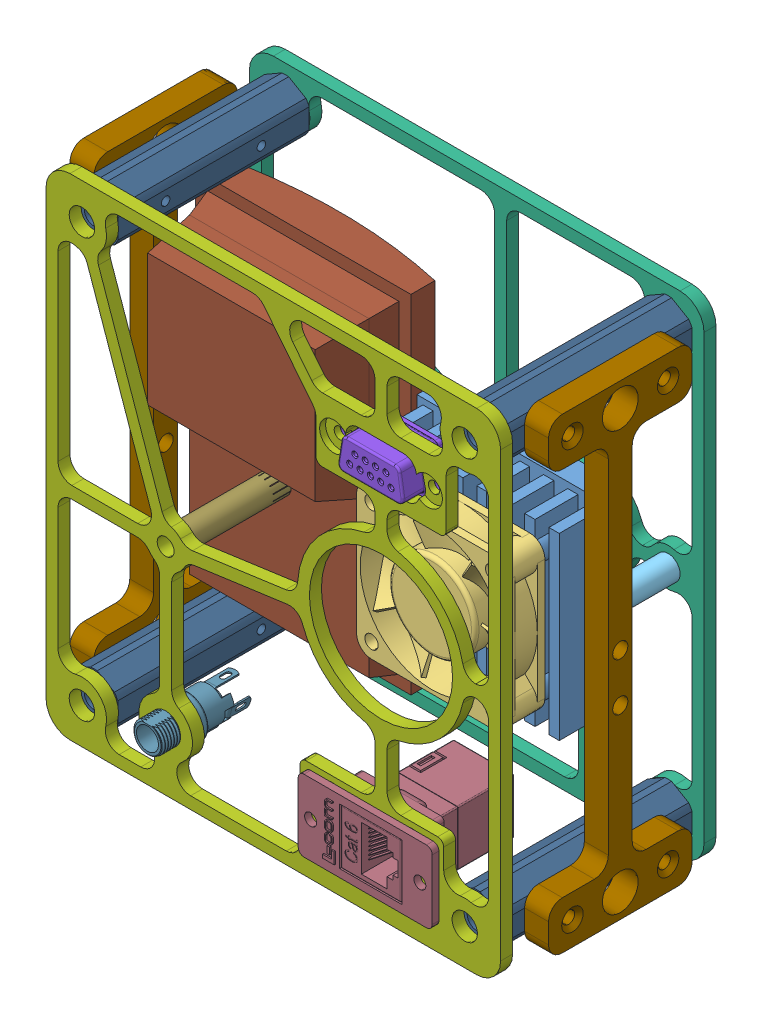
SolidWorks assembly Camera Module-Axis-No Peltier, configuration Default. Lengths in mm.
Overall size (127 130.18 62.24).
21 component instances, 15 part files, 40 mates.
Components (placement in the parent):
- Retina Fucker-No Peltier-1: Retina Fucker-No Peltier [Default] at (41.7658 96.3221 44.3342) x (-1 0 0) z (0 -1 0) size (50.8 43.67 52.39)
  - LED Interface Plate-No Peltier-1: LED Interface Plate-No Peltier [Default] at (13.1908 22.1092 31.2346) size (50.8 17.78 52.39)
  - LZ4-40G108-0000-1: LZ4-40G108-0000 [Default] at (13.1908 28.4592 31.2346) size (19.46 5.4 19.4)
  - 1939K170_DC EQUIPMENT COOLING FAN-1: 1939K170_DC EQUIPMENT COOLING FAN [Default] at (13.1908 10.6792 31.2346) x (1 0 0) z (0 -1 0) size (40 40 10.64)
  - Reflector-1: Reflector [Default] at (13.1908 30.2092 31.2346) x (0.991681 0 -0.128723) z (0.128723 0 0.991681) size (16.67 13.5 16.67)
  - Front Mounting Spacer-1: Front Mounting Spacer [Default] at (-9.0342 28.4592 31.2346) x (1 0 0) z (0 1 0) size (6.35 6.35 12.7)
  - Front Mounting Spacer-2: Front Mounting Spacer [Default] at (13.1908 28.4592 53.4596) x (1 0 0) z (0 1 0) size (6.35 6.35 12.7)
  - Front Mounting Spacer-3: Front Mounting Spacer [Default] at (35.4158 28.4592 31.2346) x (1 0 0) z (0 1 0) size (6.35 6.35 12.7)
- Front Mounting Plate-Axis-1: Front Mounting Plate-Axis [Default] at (0 65.0875 3.175) x (0 1 0) z (0 0 -1) size (130.18 120.65 3.17)
- Back Mounting Plate-Axis-1: Back Mounting Plate-Axis [Default] at (0 65.0875 57.15) x (0 1 0) z (0 0 -1) size (130.18 120.65 3.17)
- COM DB-9 female-1: COM DB-9 female [По умолчанию] at (28.5782 104.775 53.475) x (-1 0 0) z (0 0 1) size (30 12.5 15.41)
- Side Mounting Plate-Axis-3: Side Mounting Plate-Axis [Default] at (57.15 65.0875 28.575) x (0 1 0) z (1 0 0) size (123.83 38.1 6.35)
- Side Mounting Plate-Axis-2: Side Mounting Plate-Axis [Default] at (-57.15 65.0875 28.575) x (0 1 0) z (-1 0 0) size (123.83 38.1 6.35)
- Camera Module Spacer-Axis-No Peltier-9: Camera Module Spacer-Axis-No Peltier [Default] at (50.8 120.65 28.575) x (0.866025 0.5 0) z (0 0 1) size (13.75 12.7 50.8)
- Camera Module Spacer-Axis-No Peltier-11: Camera Module Spacer-Axis-No Peltier [Default] at (50.8 9.525 28.575) x (0.866025 0.5 0) z (0 0 1) size (13.75 12.7 50.8)
- Camera Module Spacer-Axis-No Peltier-10: Camera Module Spacer-Axis-No Peltier [Default] at (-50.8 120.65 28.575) x (0.866025 0.5 0) z (0 0 1) size (13.75 12.7 50.8)
- Camera Module Spacer-Axis-No Peltier-8: Camera Module Spacer-Axis-No Peltier [Default] at (-50.8 9.525 28.575) x (0.866025 0.5 0) z (0 0 1) size (13.75 12.7 50.8)
- Axis M1013-1: Axis M1013 [Default] at (-28.575 82.55 11.1125) size (57.15 92.08 38.1)
- Axis Standoff-1: Axis Standoff [Default] at (-28.575 57.15 53.975) x (1 0 0) z (0 1 0) size (6.35 28.57 6.35)
- ECF504-SC6-1: ECF504-SC6 [Default] at (26.162 15.4305 58.928) x (0 1 0) z (0 0 1) size (19.05 35.56 30.51)
- L712A-1: L712A [Default] at (-28.575 15.4305 53.975) size (11.02 11.02 23.64)
Mates (geometry in assembly coordinates):
- Coincident5: coincident anti-aligned: plane of Retina Fucker-No Peltier-1/Front Mounting Spacer-2 through (28.575 42.8625 3.175) normal (0 0 -1); plane of Front Mounting Plate-Axis-1 through (0 65.0875 3.175) normal (0 0 1)
- Parallel1: parallel anti-aligned: plane of Retina Fucker-No Peltier-1/LED Interface Plate-No Peltier-1 through (3.175 90.4875 15.875) normal (0 1 0); plane of Front Mounting Plate-Axis-1 through (60.325 0 0) normal (0 -1 0)
- Concentric5: concentric anti-aligned: circle of Retina Fucker-No Peltier-1/Reflector-1; circle of Front Mounting Plate-Axis-1
- Coincident13: coincident anti-aligned: plane of Back Mounting Plate-Axis-1 through (0 65.0875 53.975) normal (0 0 -1); plane of COM DB-9 female-1 through (28.5782 104.775 53.975) normal (0 0 1)
- Concentric15: concentric anti-aligned: circle of COM DB-9 female-1; circle of Back Mounting Plate-Axis-1
- Coincident14: coincident anti-aligned: plane of Front Mounting Plate-Axis-1 through (0 65.0875 0) normal (0 0 -1); plane of assembly through (0 0 0) normal (0 0 1)
- Parallel4: parallel anti-aligned: plane of Back Mounting Plate-Axis-1 through (35.4584 99.441 53.975) normal (0 1 0); plane of COM DB-9 female-1 through (35.7376 100.525 59.975) normal (0 -1 0)
- Coincident20: coincident anti-aligned: plane of Front Mounting Plate-Axis-1 through (60.325 0 0) normal (0 -1 0); plane of assembly through (0 0 0) normal (0 1 0)
- Coincident21: coincident aligned: plane of Front Mounting Plate-Axis-1; plane of assembly through (0 0 0) normal (1 0 0)
- Coincident26: coincident aligned: plane of Front Mounting Plate-Axis-1; plane of Side Mounting Plate-Axis-3
- Coincident28: coincident anti-aligned: plane of Front Mounting Plate-Axis-1 through (0 65.0875 3.175) normal (0 0 1); plane of Camera Module Spacer-Axis-No Peltier-11 through (50.8 9.525 3.175) normal (0 0 -1)
- Concentric22: concentric anti-aligned: cylinder of Front Mounting Plate-Axis-1 through (50.8 9.525 0) axis (0 0 -1) radius 3.3782; cylinder of Camera Module Spacer-Axis-No Peltier-11 through (50.8 9.525 53.975) axis (0 0 1) radius 2.5527
- Concentric23: concentric anti-aligned: cylinder of Back Mounting Plate-Axis-1 through (50.8 9.525 53.975) axis (0 0 -1) radius 3.3782; cylinder of Camera Module Spacer-Axis-No Peltier-11 through (50.8 9.525 53.975) axis (0 0 1) radius 2.5527
- Coincident29: coincident anti-aligned: plane of Back Mounting Plate-Axis-1 through (0 65.0875 53.975) normal (0 0 -1); plane of Camera Module Spacer-Axis-No Peltier-11 through (50.8 9.525 53.975) normal (0 0 1)
- Coincident30: coincident anti-aligned: plane of Front Mounting Plate-Axis-1 through (0 65.0875 3.175) normal (0 0 1); plane of Camera Module Spacer-Axis-No Peltier-9 through (50.8 120.65 3.175) normal (0 0 -1)
- Concentric24: concentric anti-aligned: cylinder of Front Mounting Plate-Axis-1 through (50.8 120.65 0) axis (0 0 -1) radius 3.3782; cylinder of Camera Module Spacer-Axis-No Peltier-9 through (50.8 120.65 53.975) axis (0 0 1) radius 2.5527
- Coincident31: coincident anti-aligned: plane of Front Mounting Plate-Axis-1 through (0 65.0875 3.175) normal (0 0 1); plane of Camera Module Spacer-Axis-No Peltier-10 through (-50.8 120.65 3.175) normal (0 0 -1)
- Concentric25: concentric anti-aligned: cylinder of Back Mounting Plate-Axis-1 through (-50.8 120.65 53.975) axis (0 0 -1) radius 3.3782; cylinder of Camera Module Spacer-Axis-No Peltier-10 through (-50.8 120.65 53.975) axis (0 0 1) radius 2.5527
- Coincident32: coincident anti-aligned: plane of Front Mounting Plate-Axis-1 through (0 65.0875 3.175) normal (0 0 1); plane of Camera Module Spacer-Axis-No Peltier-8 through (-50.8 9.525 3.175) normal (0 0 -1)
- Concentric26: concentric anti-aligned: cylinder of Front Mounting Plate-Axis-1 through (-50.8 9.525 0) axis (0 0 -1) radius 3.3782; cylinder of Camera Module Spacer-Axis-No Peltier-8 through (-50.8 9.525 53.975) axis (0 0 1) radius 2.5527
- Coincident34: coincident aligned: plane of Camera Module Spacer-Axis-No Peltier-9 through (57.15 118.015 53.975) normal (1 0 0); plane of Camera Module Spacer-Axis-No Peltier-11 through (57.15 6.89 53.975) normal (1 0 0)
- Coincident35: coincident anti-aligned: plane of Camera Module Spacer-Axis-No Peltier-11 through (57.15 6.89 53.975) normal (1 0 0); plane of Side Mounting Plate-Axis-3 through (57.15 65.0875 28.575) normal (-1 0 0)
- Coincident36: coincident anti-aligned: plane of Camera Module Spacer-Axis-No Peltier-8 through (-57.15 12.16 53.975) normal (-1 0 0); plane of Side Mounting Plate-Axis-2 through (-57.15 65.0875 28.575) normal (1 0 0)
- Coincident37: coincident aligned: plane of Camera Module Spacer-Axis-No Peltier-10 through (-57.15 123.285 53.975) normal (-1 0 0); plane of Camera Module Spacer-Axis-No Peltier-8 through (-57.15 12.16 53.975) normal (-1 0 0)
- Concentric27: concentric anti-aligned: cylinder of Front Mounting Plate-Axis-1 through (-50.8 120.65 0) axis (0 0 -1) radius 3.3782; cylinder of Camera Module Spacer-Axis-No Peltier-10 through (-50.8 120.65 53.975) axis (0 0 1) radius 2.5527
- Parallel6: parallel anti-aligned: plane of Front Mounting Plate-Axis-1 through (0 65.0875 0) normal (0 0 -1); plane of Side Mounting Plate-Axis-2 through (-57.15 15.875 31.75) normal (0 0 1)
- Coincident39: coincident aligned: plane of Front Mounting Plate-Axis-1; plane of Side Mounting Plate-Axis-2
- Coincident40: coincident aligned: plane of Front Mounting Plate-Axis-1; plane of Side Mounting Plate-Axis-3
- Coincident41: coincident aligned: plane of Side Mounting Plate-Axis-3; plane of Camera Module Spacer-Axis-No Peltier-9 through (50.8 120.65 28.575) normal (0 0 1)
- Coincident42: coincident anti-aligned: plane of Side Mounting Plate-Axis-2; plane of Camera Module Spacer-Axis-No Peltier-9 through (50.8 120.65 28.575) normal (0 0 1)
- Distance1: distance = 1.5875 mm aligned: plane of Axis M1013-1 through (-28.575 89.8346 1.5875) normal (0 0 -1); plane of Front Mounting Plate-Axis-1 through (0 65.0875 0) normal (0 0 -1)
- Parallel7: parallel aligned: plane of Back Mounting Plate-Axis-1 through (-60.325 0 53.975) normal (-1 0 0); plane of Axis M1013-1 through (-57.15 19.05 14.2875) normal (-1 0 0)
- Distance2: distance = 19.05 mm aligned: plane of Axis M1013-1 through (-28.575 111.125 141.2875) normal (0 1 0); plane of Front Mounting Plate-Axis-1 through (60.325 130.175 0) normal (0 1 0)
- Distance3: distance = 3.175 mm anti-aligned: plane of Axis M1013-1 through (0 19.05 14.2875) normal (1 0 0); plane of Retina Fucker-No Peltier-1/LED Interface Plate-No Peltier-1 through (3.175 39.6875 15.875) normal (-1 0 0)
- Coincident47: coincident anti-aligned: plane of Back Mounting Plate-Axis-1 through (0 65.0875 53.975) normal (0 0 -1); plane of Axis Standoff-1 through (-28.575 57.15 53.975) normal (0 0 1)
- Concentric29: concentric anti-aligned: cylinder of Axis M1013-1 through (-28.575 57.15 40.7303) axis (0 0 -1) radius 3.175; cylinder of Axis Standoff-1 through (-28.575 57.15 25.4) axis (0 0 1) radius 3.175
- Coincident48: coincident anti-aligned: plane of Back Mounting Plate-Axis-1 through (0 65.0875 57.15) normal (0 0 1); plane of ECF504-SC6-1 through (42.418 7.4295 57.15) normal (0 0 -1)
- Coincident51: coincident anti-aligned: plane of Back Mounting Plate-Axis-1 through (0 65.0875 53.975) normal (0 0 -1); plane of L712A-1 through (-33.7058 15.4305 53.975) normal (0 0 1)
- Concentric30: concentric aligned: cylinder of Back Mounting Plate-Axis-1 through (-28.575 15.4305 57.15) axis (0 0 1) radius 3.9688; circle of L712A-1
- Concentric31: concentric anti-aligned: circle of Back Mounting Plate-Axis-1; circle of ECF504-SC6-1
